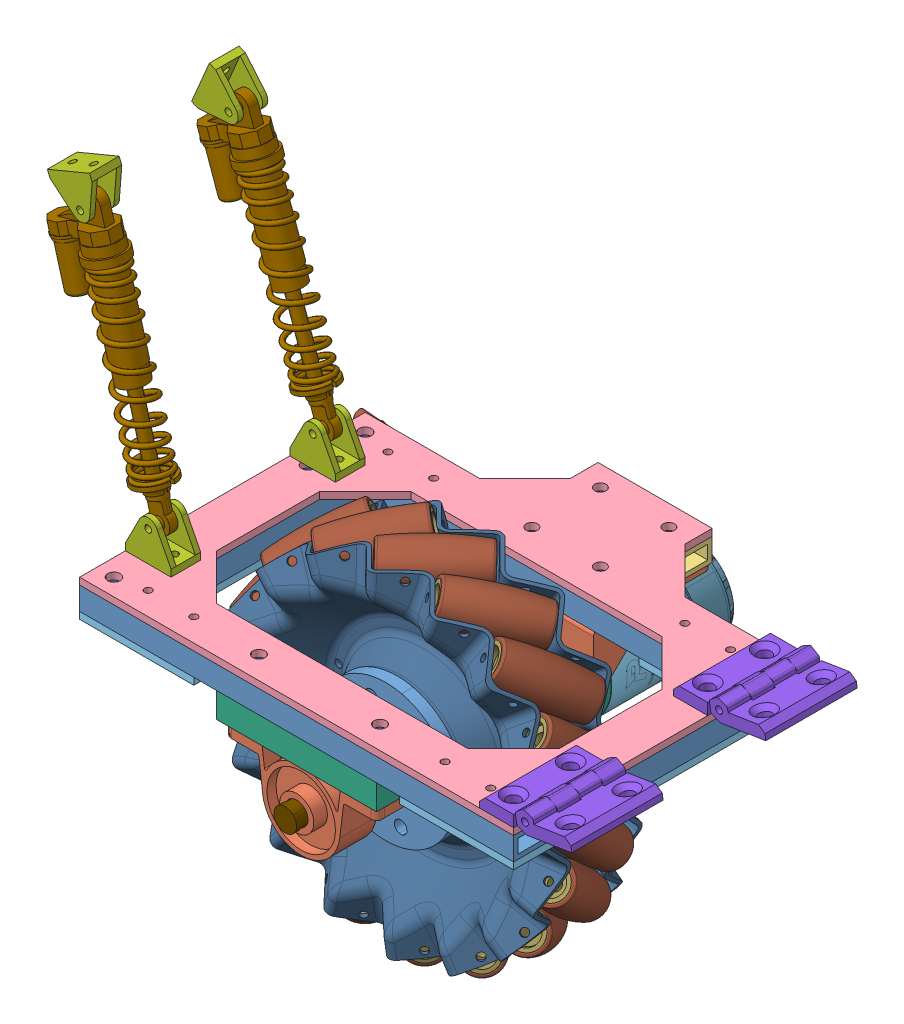
SolidWorks assembly suspension-R, configuration 默认. Lengths in mm.
Overall size (264.55 284.01 183.1).
217 component instances, 35 part files, 56 mates.
Components (placement in the parent):
- Al_Structure-1: Al_Structure [默认] at (-46.393 -16.6731 0) size (190 10 125)
- 3508_10电机座-1: 3508_10电机座 [Default] at (24.7457 -16.6731 39.834) x (-1 0 0) z (0 0 1) size (50 52 52)
- M3508直流无刷减速电机-1: M3508直流无刷减速电机 [默认] at (-63.9604 -40.3546 -130.941) x (-0.381788 -0.92425 0) z (0 0 1) size (81.79 158.79 98.4)
  - M3508直流无刷减速电机.STEP-1: M3508直流无刷减速电机.STEP [Default] at origin size (81.79 158.79 98.4)
    - 2.STEP-1: 2.STEP [Default] at (-1.7887 18.2683 50.441) x (-0.381788 0.92425 0) z (0.92425 0.381788 0) size (59.4 63.3 59.4)
      - 26.STEP-1: 26.STEP [Default] at (0 27 0) x (-0.381788 0 0.92425) z (-0.92425 0 -0.381788) size (22 6 22)
        - 27.STEP-1: 27.STEP [默认] at origin size (22 6 22)
        - 28.STEP-1: 28.STEP [默认] at (0 2.5 0) size (20 0.2 20)
        - 28.STEP-2: 28.STEP [默认] at (0 -2.7 0) size (20 0.2 20)
      - 26.STEP-2: 26.STEP [Default] at (0 34.5 0) x (-0.381788 0 0.92425) z (-0.92425 0 -0.381788) size (22 6 22)
        - 27.STEP-1: 27.STEP [默认] at origin size (22 6 22)
        - 28.STEP-1: 28.STEP [默认] at (0 2.5 0) size (20 0.2 20)
        - 28.STEP-2: 28.STEP [默认] at (0 -2.7 0) size (20 0.2 20)
      - 23.STEP-1: 23.STEP [默认] at origin size (42.01 26 42)
      - 16.STEP-1: 16.STEP [默认] at (0 31 0) x (-0.707107 0 0.707107) z (0 1 0) size (42 42 14)
      - 25.STEP-1: 25.STEP [默认] at (0 38.5 0) x (0 0 1) z (-1 0 0) size (16.7 1 13.43)
      - 17.STEP-1: 17.STEP [默认] at (0 19.3 0) x (-1 0 0) z (0 0 -1) size (26 44 26)
      - 24.STEP-1: 24.STEP [默认] at (0 37.71 0) x (0 1 0) z (0.381788 0 -0.92425) size (0.42 16 16)
      - 18.STEP-1: 18.STEP [默认] at (12.3744 22 12.3744) x (-0.381788 0 0.92425) z (-0.92425 0 -0.381788) size (5.5 12 5.5)
      - 18.STEP-2: 18.STEP [默认] at (12.3744 22 -12.3744) x (0.92425 0 0.381788) z (-0.381788 0 0.92425) size (5.5 12 5.5)
      - 18.STEP-3: 18.STEP [默认] at (-12.3744 22 -12.3744) x (0.381788 0 -0.92425) z (0.92425 0 0.381788) size (5.5 12 5.5)
      - 18.STEP-4: 18.STEP [默认] at (-12.3744 22 12.3744) x (-0.92425 0 -0.381788) z (0.381788 0 -0.92425) size (5.5 12 5.5)
    - 5.STEP-1: 5.STEP [Default] at (56.824 -105.7062 43.091) x (0.954008 0.299781 0) z (-0.299781 0.954008 0) size (12.31 5.48 111.01)
      - 19.STEP-1: 19.STEP [默认] at origin size (12.31 5.48 13.41)
      - 15.STEP-1: 15.STEP [默认] at (-22.7519 0 22.9937) x (-1 0 0) z (0 0 -1) size (2.5 2.5 100)
      - 15.STEP-2: 15.STEP [默认] at (-18.7519 0 22.9937) x (0 1 0) z (0 0 -1) size (2.5 2.5 100)
      - 15.STEP-3: 15.STEP [默认] at (-14.7519 0 22.9937) x (-1 0 0) z (0 0 -1) size (2.5 2.5 100)
      - 20.STEP-1: 20.STEP [默认] at (-1.9783 -5.4851 11.3276) x (1 0 0) z (0 0 -1) size (11.93 4.93 6.5)
    - 1.STEP-1: 1.STEP [默认] at (-1.7887 18.2683 48.441) x (0.923508 -0.383579 0) z (0 0 1) size (42 42 43.4)
    - 4.STEP-1: 4.STEP [默认] at (-1.7887 18.2683 39.841) x (-0.923508 0.383579 0) z (0.383579 0.923508 0) size (13.16 4.25 21.29)
    - 3.STEP-1: 3.STEP [默认] at (4.5067 -1.7659 43.091) x (0.299781 -0.954008 0) z (0.954008 0.299781 0) size (5.77 4 14.5)
- 3510D孔联轴器-1: 3510D孔联轴器 [Default] at (-128.3393 -63.9318 -10.2) x (0.685829 0.727763 0) z (-0.727763 0.685829 0) size (60 27 60)
- 10mm钢制联轴器-1: 10mm钢制联轴器 [默认] at (-49.6804 -47.7533 1.2992) x (0.685829 0.727763 0) z (0 0 1) size (81.96 81.96 49.1)
  - 10mm钢制联轴器.STEP-1: 10mm钢制联轴器.STEP [Default] at origin size (81.96 81.96 49.1)
    - __________.STEP-1: __________.STEP [Default] at (3.7664 -0.9677 32.1012) size (24 24 44.1)
    - 3510______ ____2.STEP-1: 3510______ ____2.STEP [Default] at (9.8274 82.7684 22.1012) x (0.5 -0.866025 0) z (0.866025 0.5 0) size (60 5 60)
- 10mmBearingSet-1: 10mmBearingSet [默认] at (-47.6247 -31.9408 44.5) x (-1 0 0) z (0 0 1) size (67 35 18)
- 电机座垫铝管-1: 电机座垫铝管 [Default] at (24.7457 -16.6731 39.834) x (1 0 0) z (0 1 0) size (50 20 10)
- 玻纤上板-1: 玻纤上板 [Default] at (-46.393 -6.6731 0) x (1 0 0) z (0 1 0) size (190 157 3)
- 玻纤下板-1: 玻纤下板 [Default] at (-46.393 -16.6731 0) x (-1 0 0) z (0 -1 0) size (50 125 3)
- 玻纤下板-2: 玻纤下板 [Default] at (-46.393 -16.6731 0) x (1 0 0) z (0 -1 0) size (50 125 3)
- 3DPrinting垫片-1: 3DPrinting垫片 [Default] at (-46.393 -16.6731 0) x (-1 0 0) z (0 -1 0) size (70 20 11)
- 3mm固定座-1: 3mm固定座 [Default] at (-166.7361 -3.6731 11.7194) size (20 17.54 13)
- 3mm固定座-2: 3mm固定座 [Default] at (-166.7361 -3.6731 83.7194) size (20 17.54 13)
- 铰链-1: 铰链 [默认] at (42.216 2.468 -82.5) x (-1 0 0) z (0 0 1) size (40.48 12.73 40)
  - 铰链-1: 铰链 [默认] at (-11.391 1.5222 20) size (24 9.08 40)
  - 铰链-2: 铰链 [默认] at (-11.391 1.5222 60) x (-0.987641 -0.156733 0) z (0 0 -1) size (24 9.08 40)
- 铰链-2: 铰链 [默认] at (42.216 2.468 2.5) x (-1 0 0) z (0 0 1) size (40.48 12.73 40)
  - 铰链-1: 铰链 [默认] at (-11.391 1.5222 20) size (24 9.08 40)
  - 铰链-2: 铰链 [默认] at (-11.391 1.5222 60) x (-0.987641 -0.156733 0) z (0 0 -1) size (24 9.08 40)
- 孔距110mm负压避震器.-1: 孔距110mm负压避震器. [默认] at (-170.847 94.2339 -2.4) x (-0.96253 -0.271174 0) z (0 0 1) size (30.38 119.45 17)
- 孔距110mm负压避震器.-2: 孔距110mm负压避震器. [默认] at (-176.4374 91.3946 -74.4) x (-0.942156 -0.335174 0) z (0 0 1) size (30.38 119.45 17)
- 3mm固定座-3: 3mm固定座 [Default] at (-133.7096 141.372 83.7194) x (-0.923129 -0.38449 0) z (0 0 1) size (20 17.54 13)
- 3mm固定座-4: 3mm固定座 [Default] at (-166.7199 150.9953 11.7194) x (-0.390129 -0.92076 0) z (0 0 1) size (20 17.54 13)
- 麦轮组装左-1: 麦轮组装左 [默认] at (-29.0896 -59.734 -126.7518) x (0.945939 -0.324344 0) z (0 0 1) size (168 168 53.18)
  - 麦轮钣金-1: 麦轮钣金 [默认] at (-20.9276 7.6858 132.4522) size (142.88 142.88 24.05)
  - 麦轮钣金-2: 麦轮钣金 [默认] at (-20.9276 7.6858 129.2518) x (-0.980785 -0.19509 0) z (0 0 -1) size (142.88 142.88 24.05)
  - 滚花橡胶轮组装-1: 滚花橡胶轮组装 [默认] at (60.4121 -1.9858 154.8754) x (0.932849 -0.320965 -0.163627) z (-0.338043 -0.622763 -0.705615) size (18.5 18.5 53)
    - 滚花橡胶轮外-1: 滚花橡胶轮外 [默认] at (-9.896 1.7835 38.5971) size (18.5 18.5 38)
    - 滚花铝柱-1: 滚花铝柱 [默认] at (-9.896 1.7835 38) x (0.787441 0.61639 0) z (-0.61639 0.787441 0) size (13 38 13)
    - 轴承5X10X4-1: 轴承5X10X4 [默认] at (-9.896 1.7835 55) x (0.442498 0.896769 0) z (-0.896769 0.442498 0) size (10 4 10)
    - 轴承5X10X4-2: 轴承5X10X4 [默认] at (-9.896 1.7835 21) x (0.442498 0.896769 0) z (-0.896769 0.442498 0) size (10 4 10)
    - 铜管3X5-1: 铜管3X5 [默认] at (-9.896 1.7835 38) x (0.823254 0.567673 0) z (-0.567673 0.823254 0) size (5 38 5)
    - 螺丝-1: 螺丝 [默认] at (-9.896 1.7835 59.6) x (-0.462621 0.886556 0) z (0 0 1) size (5.5 5.5 53)
    - 垫片-1: 垫片 [默认] at (-9.896 1.7835 57) x (1 0 0) z (0 -1 0) size (7 0.8 7)
    - 垫片-2: 垫片 [默认] at (-9.896 1.7835 19) x (0.746862 -0.664979 0) z (0.664979 0.746862 0) size (7 0.8 7)
    - 螺母-1: 螺母 [默认] at (-9.896 1.7835 16.2) x (-0.766894 0.641774 0) z (0 0 -1) size (6.35 5.5 4.25)
  - 滚花橡胶轮组装-2: 滚花橡胶轮组装 [默认] at (57.9216 29.8777 154.8754) x (0.984668 0.060453 -0.163627) z (-0.073989 -0.704722 -0.705615) size (18.5 18.5 53)
    - 滚花橡胶轮外-1: 滚花橡胶轮外 [默认] at (-9.896 1.7835 38.5971) size (18.5 18.5 38)
    - 滚花铝柱-1: 滚花铝柱 [默认] at (-9.896 1.7835 38) x (0.787441 0.61639 0) z (-0.61639 0.787441 0) size (13 38 13)
    - 轴承5X10X4-1: 轴承5X10X4 [默认] at (-9.896 1.7835 55) x (0.442498 0.896769 0) z (-0.896769 0.442498 0) size (10 4 10)
    - 轴承5X10X4-2: 轴承5X10X4 [默认] at (-9.896 1.7835 21) x (0.442498 0.896769 0) z (-0.896769 0.442498 0) size (10 4 10)
    - 铜管3X5-1: 铜管3X5 [默认] at (-9.896 1.7835 38) x (0.823254 0.567673 0) z (-0.567673 0.823254 0) size (5 38 5)
    - 螺丝-1: 螺丝 [默认] at (-9.896 1.7835 59.6) x (-0.462621 0.886556 0) z (0 0 1) size (5.5 5.5 53)
    - 垫片-1: 垫片 [默认] at (-9.896 1.7835 57) x (1 0 0) z (0 -1 0) size (7 0.8 7)
    - 垫片-2: 垫片 [默认] at (-9.896 1.7835 19) x (0.746862 -0.664979 0) z (0.664979 0.746862 0) size (7 0.8 7)
    - 螺母-1: 螺母 [默认] at (-9.896 1.7835 16.2) x (-0.766894 0.641774 0) z (0 0 -1) size (6.35 5.5 4.25)
  - 滚花橡胶轮组装-3: 滚花橡胶轮组装 [默认] at (43.4271 58.3628 154.8754) x (0.88658 0.432668 -0.163627) z (0.201328 -0.679392 -0.705615) size (18.5 18.5 53)
    - 滚花橡胶轮外-1: 滚花橡胶轮外 [默认] at (-9.896 1.7835 38.5971) size (18.5 18.5 38)
    - 滚花铝柱-1: 滚花铝柱 [默认] at (-9.896 1.7835 38) x (0.787441 0.61639 0) z (-0.61639 0.787441 0) size (13 38 13)
    - 轴承5X10X4-1: 轴承5X10X4 [默认] at (-9.896 1.7835 55) x (0.442498 0.896769 0) z (-0.896769 0.442498 0) size (10 4 10)
    - 轴承5X10X4-2: 轴承5X10X4 [默认] at (-9.896 1.7835 21) x (0.442498 0.896769 0) z (-0.896769 0.442498 0) size (10 4 10)
    - 铜管3X5-1: 铜管3X5 [默认] at (-9.896 1.7835 38) x (0.823254 0.567673 0) z (-0.567673 0.823254 0) size (5 38 5)
    - 螺丝-1: 螺丝 [默认] at (-9.896 1.7835 59.6) x (-0.462621 0.886556 0) z (0 0 1) size (5.5 5.5 53)
    - 垫片-1: 垫片 [默认] at (-9.896 1.7835 57) x (1 0 0) z (0 -1 0) size (7 0.8 7)
    - 垫片-2: 垫片 [默认] at (-9.896 1.7835 19) x (0.746862 -0.664979 0) z (0.664979 0.746862 0) size (7 0.8 7)
    - 螺母-1: 螺母 [默认] at (-9.896 1.7835 16.2) x (-0.766894 0.641774 0) z (0 0 -1) size (6.35 5.5 4.25)
  - 滚花橡胶轮组装-4: 滚花橡胶轮组装 [默认] at (19.1352 79.1327 154.8754) x (0.653519 0.739013 -0.163627) z (0.445995 -0.550632 -0.705615) size (18.5 18.5 53)
    - 滚花橡胶轮外-1: 滚花橡胶轮外 [默认] at (-9.896 1.7835 38.5971) size (18.5 18.5 38)
    - 滚花铝柱-1: 滚花铝柱 [默认] at (-9.896 1.7835 38) x (0.787441 0.61639 0) z (-0.61639 0.787441 0) size (13 38 13)
    - 轴承5X10X4-1: 轴承5X10X4 [默认] at (-9.896 1.7835 55) x (0.442498 0.896769 0) z (-0.896769 0.442498 0) size (10 4 10)
    - 轴承5X10X4-2: 轴承5X10X4 [默认] at (-9.896 1.7835 21) x (0.442498 0.896769 0) z (-0.896769 0.442498 0) size (10 4 10)
    - 铜管3X5-1: 铜管3X5 [默认] at (-9.896 1.7835 38) x (0.823254 0.567673 0) z (-0.567673 0.823254 0) size (5 38 5)
    - 螺丝-1: 螺丝 [默认] at (-9.896 1.7835 59.6) x (-0.462621 0.886556 0) z (0 0 1) size (5.5 5.5 53)
    - 垫片-1: 垫片 [默认] at (-9.896 1.7835 57) x (1 0 0) z (0 -1 0) size (7 0.8 7)
    - 垫片-2: 垫片 [默认] at (-9.896 1.7835 19) x (0.746862 -0.664979 0) z (0.664979 0.746862 0) size (7 0.8 7)
    - 螺母-1: 螺母 [默认] at (-9.896 1.7835 16.2) x (-0.766894 0.641774 0) z (0 0 -1) size (6.35 5.5 4.25)
  - 滚花橡胶轮组装-5: 滚花橡胶轮组装 [默认] at (-11.256 89.0255 154.8754) x (0.320965 0.932849 -0.163627) z (0.622763 -0.338043 -0.705615) size (18.5 18.5 53)
    - 滚花橡胶轮外-1: 滚花橡胶轮外 [默认] at (-9.896 1.7835 38.5971) size (18.5 18.5 38)
    - 滚花铝柱-1: 滚花铝柱 [默认] at (-9.896 1.7835 38) x (0.787441 0.61639 0) z (-0.61639 0.787441 0) size (13 38 13)
    - 轴承5X10X4-1: 轴承5X10X4 [默认] at (-9.896 1.7835 55) x (0.442498 0.896769 0) z (-0.896769 0.442498 0) size (10 4 10)
    - 轴承5X10X4-2: 轴承5X10X4 [默认] at (-9.896 1.7835 21) x (0.442498 0.896769 0) z (-0.896769 0.442498 0) size (10 4 10)
    - 铜管3X5-1: 铜管3X5 [默认] at (-9.896 1.7835 38) x (0.823254 0.567673 0) z (-0.567673 0.823254 0) size (5 38 5)
    - 螺丝-1: 螺丝 [默认] at (-9.896 1.7835 59.6) x (-0.462621 0.886556 0) z (0 0 1) size (5.5 5.5 53)
    - 垫片-1: 垫片 [默认] at (-9.896 1.7835 57) x (1 0 0) z (0 -1 0) size (7 0.8 7)
    - 垫片-2: 垫片 [默认] at (-9.896 1.7835 19) x (0.746862 -0.664979 0) z (0.664979 0.746862 0) size (7 0.8 7)
    - 螺母-1: 螺母 [默认] at (-9.896 1.7835 16.2) x (-0.766894 0.641774 0) z (0 0 -1) size (6.35 5.5 4.25)
  - 滚花橡胶轮组装-6: 滚花橡胶轮组装 [默认] at (-43.1195 86.535 154.8754) x (-0.060453 0.984668 -0.163627) z (0.704722 -0.073989 -0.705615) size (18.5 18.5 53)
    - 滚花橡胶轮外-1: 滚花橡胶轮外 [默认] at (-9.896 1.7835 38.5971) size (18.5 18.5 38)
    - 滚花铝柱-1: 滚花铝柱 [默认] at (-9.896 1.7835 38) x (0.787441 0.61639 0) z (-0.61639 0.787441 0) size (13 38 13)
    - 轴承5X10X4-1: 轴承5X10X4 [默认] at (-9.896 1.7835 55) x (0.442498 0.896769 0) z (-0.896769 0.442498 0) size (10 4 10)
    - 轴承5X10X4-2: 轴承5X10X4 [默认] at (-9.896 1.7835 21) x (0.442498 0.896769 0) z (-0.896769 0.442498 0) size (10 4 10)
    - 铜管3X5-1: 铜管3X5 [默认] at (-9.896 1.7835 38) x (0.823254 0.567673 0) z (-0.567673 0.823254 0) size (5 38 5)
    - 螺丝-1: 螺丝 [默认] at (-9.896 1.7835 59.6) x (-0.462621 0.886556 0) z (0 0 1) size (5.5 5.5 53)
    - 垫片-1: 垫片 [默认] at (-9.896 1.7835 57) x (1 0 0) z (0 -1 0) size (7 0.8 7)
    - 垫片-2: 垫片 [默认] at (-9.896 1.7835 19) x (0.746862 -0.664979 0) z (0.664979 0.746862 0) size (7 0.8 7)
    - 螺母-1: 螺母 [默认] at (-9.896 1.7835 16.2) x (-0.766894 0.641774 0) z (0 0 -1) size (6.35 5.5 4.25)
  - 滚花橡胶轮组装-7: 滚花橡胶轮组装 [默认] at (-71.6045 72.0405 154.8754) x (-0.432668 0.88658 -0.163627) z (0.679392 0.201328 -0.705615) size (18.5 18.5 53)
    - 滚花橡胶轮外-1: 滚花橡胶轮外 [默认] at (-9.896 1.7835 38.5971) size (18.5 18.5 38)
    - 滚花铝柱-1: 滚花铝柱 [默认] at (-9.896 1.7835 38) x (0.787441 0.61639 0) z (-0.61639 0.787441 0) size (13 38 13)
    - 轴承5X10X4-1: 轴承5X10X4 [默认] at (-9.896 1.7835 55) x (0.442498 0.896769 0) z (-0.896769 0.442498 0) size (10 4 10)
    - 轴承5X10X4-2: 轴承5X10X4 [默认] at (-9.896 1.7835 21) x (0.442498 0.896769 0) z (-0.896769 0.442498 0) size (10 4 10)
    - 铜管3X5-1: 铜管3X5 [默认] at (-9.896 1.7835 38) x (0.823254 0.567673 0) z (-0.567673 0.823254 0) size (5 38 5)
    - 螺丝-1: 螺丝 [默认] at (-9.896 1.7835 59.6) x (-0.462621 0.886556 0) z (0 0 1) size (5.5 5.5 53)
    - 垫片-1: 垫片 [默认] at (-9.896 1.7835 57) x (1 0 0) z (0 -1 0) size (7 0.8 7)
    - 垫片-2: 垫片 [默认] at (-9.896 1.7835 19) x (0.746862 -0.664979 0) z (0.664979 0.746862 0) size (7 0.8 7)
    - 螺母-1: 螺母 [默认] at (-9.896 1.7835 16.2) x (-0.766894 0.641774 0) z (0 0 -1) size (6.35 5.5 4.25)
  - 滚花橡胶轮组装-8: 滚花橡胶轮组装 [默认] at (-92.3745 47.7486 154.8754) x (-0.739013 0.653519 -0.163627) z (0.550632 0.445995 -0.705615) size (18.5 18.5 53)
    - 滚花橡胶轮外-1: 滚花橡胶轮外 [默认] at (-9.896 1.7835 38.5971) size (18.5 18.5 38)
    - 滚花铝柱-1: 滚花铝柱 [默认] at (-9.896 1.7835 38) x (0.787441 0.61639 0) z (-0.61639 0.787441 0) size (13 38 13)
    - 轴承5X10X4-1: 轴承5X10X4 [默认] at (-9.896 1.7835 55) x (0.442498 0.896769 0) z (-0.896769 0.442498 0) size (10 4 10)
    - 轴承5X10X4-2: 轴承5X10X4 [默认] at (-9.896 1.7835 21) x (0.442498 0.896769 0) z (-0.896769 0.442498 0) size (10 4 10)
    - 铜管3X5-1: 铜管3X5 [默认] at (-9.896 1.7835 38) x (0.823254 0.567673 0) z (-0.567673 0.823254 0) size (5 38 5)
    - 螺丝-1: 螺丝 [默认] at (-9.896 1.7835 59.6) x (-0.462621 0.886556 0) z (0 0 1) size (5.5 5.5 53)
    - 垫片-1: 垫片 [默认] at (-9.896 1.7835 57) x (1 0 0) z (0 -1 0) size (7 0.8 7)
    - 垫片-2: 垫片 [默认] at (-9.896 1.7835 19) x (0.746862 -0.664979 0) z (0.664979 0.746862 0) size (7 0.8 7)
    - 螺母-1: 螺母 [默认] at (-9.896 1.7835 16.2) x (-0.766894 0.641774 0) z (0 0 -1) size (6.35 5.5 4.25)
  - 滚花橡胶轮组装-9: 滚花橡胶轮组装 [默认] at (-102.2673 17.3574 154.8754) x (-0.932849 0.320965 -0.163627) z (0.338043 0.622763 -0.705615) size (18.5 18.5 53)
    - 滚花橡胶轮外-1: 滚花橡胶轮外 [默认] at (-9.896 1.7835 38.5971) size (18.5 18.5 38)
    - 滚花铝柱-1: 滚花铝柱 [默认] at (-9.896 1.7835 38) x (0.787441 0.61639 0) z (-0.61639 0.787441 0) size (13 38 13)
    - 轴承5X10X4-1: 轴承5X10X4 [默认] at (-9.896 1.7835 55) x (0.442498 0.896769 0) z (-0.896769 0.442498 0) size (10 4 10)
    - 轴承5X10X4-2: 轴承5X10X4 [默认] at (-9.896 1.7835 21) x (0.442498 0.896769 0) z (-0.896769 0.442498 0) size (10 4 10)
    - 铜管3X5-1: 铜管3X5 [默认] at (-9.896 1.7835 38) x (0.823254 0.567673 0) z (-0.567673 0.823254 0) size (5 38 5)
    - 螺丝-1: 螺丝 [默认] at (-9.896 1.7835 59.6) x (-0.462621 0.886556 0) z (0 0 1) size (5.5 5.5 53)
    - 垫片-1: 垫片 [默认] at (-9.896 1.7835 57) x (1 0 0) z (0 -1 0) size (7 0.8 7)
    - 垫片-2: 垫片 [默认] at (-9.896 1.7835 19) x (0.746862 -0.664979 0) z (0.664979 0.746862 0) size (7 0.8 7)
    - 螺母-1: 螺母 [默认] at (-9.896 1.7835 16.2) x (-0.766894 0.641774 0) z (0 0 -1) size (6.35 5.5 4.25)
  - 滚花橡胶轮组装-10: 滚花橡胶轮组装 [默认] at (-99.7768 -14.5061 154.8754) x (-0.984668 -0.060453 -0.163627) z (0.073989 0.704722 -0.705615) size (18.5 18.5 53)
    - 滚花橡胶轮外-1: 滚花橡胶轮外 [默认] at (-9.896 1.7835 38.5971) size (18.5 18.5 38)
    - 滚花铝柱-1: 滚花铝柱 [默认] at (-9.896 1.7835 38) x (0.787441 0.61639 0) z (-0.61639 0.787441 0) size (13 38 13)
    - 轴承5X10X4-1: 轴承5X10X4 [默认] at (-9.896 1.7835 55) x (0.442498 0.896769 0) z (-0.896769 0.442498 0) size (10 4 10)
    - 轴承5X10X4-2: 轴承5X10X4 [默认] at (-9.896 1.7835 21) x (0.442498 0.896769 0) z (-0.896769 0.442498 0) size (10 4 10)
    - 铜管3X5-1: 铜管3X5 [默认] at (-9.896 1.7835 38) x (0.823254 0.567673 0) z (-0.567673 0.823254 0) size (5 38 5)
    - 螺丝-1: 螺丝 [默认] at (-9.896 1.7835 59.6) x (-0.462621 0.886556 0) z (0 0 1) size (5.5 5.5 53)
    - 垫片-1: 垫片 [默认] at (-9.896 1.7835 57) x (1 0 0) z (0 -1 0) size (7 0.8 7)
    - 垫片-2: 垫片 [默认] at (-9.896 1.7835 19) x (0.746862 -0.664979 0) z (0.664979 0.746862 0) size (7 0.8 7)
    - 螺母-1: 螺母 [默认] at (-9.896 1.7835 16.2) x (-0.766894 0.641774 0) z (0 0 -1) size (6.35 5.5 4.25)
  - 滚花橡胶轮组装-11: 滚花橡胶轮组装 [默认] at (-85.2823 -42.9912 154.8754) x (-0.88658 -0.432668 -0.163627) z (-0.201328 0.679392 -0.705615) size (18.5 18.5 53)
    - 滚花橡胶轮外-1: 滚花橡胶轮外 [默认] at (-9.896 1.7835 38.5971) size (18.5 18.5 38)
    - 滚花铝柱-1: 滚花铝柱 [默认] at (-9.896 1.7835 38) x (0.787441 0.61639 0) z (-0.61639 0.787441 0) size (13 38 13)
    - 轴承5X10X4-1: 轴承5X10X4 [默认] at (-9.896 1.7835 55) x (0.442498 0.896769 0) z (-0.896769 0.442498 0) size (10 4 10)
    - 轴承5X10X4-2: 轴承5X10X4 [默认] at (-9.896 1.7835 21) x (0.442498 0.896769 0) z (-0.896769 0.442498 0) size (10 4 10)
    - 铜管3X5-1: 铜管3X5 [默认] at (-9.896 1.7835 38) x (0.823254 0.567673 0) z (-0.567673 0.823254 0) size (5 38 5)
    - 螺丝-1: 螺丝 [默认] at (-9.896 1.7835 59.6) x (-0.462621 0.886556 0) z (0 0 1) size (5.5 5.5 53)
    - 垫片-1: 垫片 [默认] at (-9.896 1.7835 57) x (1 0 0) z (0 -1 0) size (7 0.8 7)
    - 垫片-2: 垫片 [默认] at (-9.896 1.7835 19) x (0.746862 -0.664979 0) z (0.664979 0.746862 0) size (7 0.8 7)
    - 螺母-1: 螺母 [默认] at (-9.896 1.7835 16.2) x (-0.766894 0.641774 0) z (0 0 -1) size (6.35 5.5 4.25)
  - 滚花橡胶轮组装-12: 滚花橡胶轮组装 [默认] at (-60.9904 -63.7611 154.8754) x (-0.653519 -0.739013 -0.163627) z (-0.445995 0.550632 -0.705615) size (18.5 18.5 53)
    - 滚花橡胶轮外-1: 滚花橡胶轮外 [默认] at (-9.896 1.7835 38.5971) size (18.5 18.5 38)
    - 滚花铝柱-1: 滚花铝柱 [默认] at (-9.896 1.7835 38) x (0.787441 0.61639 0) z (-0.61639 0.787441 0) size (13 38 13)
    - 轴承5X10X4-1: 轴承5X10X4 [默认] at (-9.896 1.7835 55) x (0.442498 0.896769 0) z (-0.896769 0.442498 0) size (10 4 10)
    - 轴承5X10X4-2: 轴承5X10X4 [默认] at (-9.896 1.7835 21) x (0.442498 0.896769 0) z (-0.896769 0.442498 0) size (10 4 10)
    - 铜管3X5-1: 铜管3X5 [默认] at (-9.896 1.7835 38) x (0.823254 0.567673 0) z (-0.567673 0.823254 0) size (5 38 5)
    - 螺丝-1: 螺丝 [默认] at (-9.896 1.7835 59.6) x (-0.462621 0.886556 0) z (0 0 1) size (5.5 5.5 53)
    - 垫片-1: 垫片 [默认] at (-9.896 1.7835 57) x (1 0 0) z (0 -1 0) size (7 0.8 7)
    - 垫片-2: 垫片 [默认] at (-9.896 1.7835 19) x (0.746862 -0.664979 0) z (0.664979 0.746862 0) size (7 0.8 7)
    - 螺母-1: 螺母 [默认] at (-9.896 1.7835 16.2) x (-0.766894 0.641774 0) z (0 0 -1) size (6.35 5.5 4.25)
  - 滚花橡胶轮组装-13: 滚花橡胶轮组装 [默认] at (-30.5992 -73.6539 154.8754) x (-0.320965 -0.932849 -0.163627) z (-0.622763 0.338043 -0.705615) size (18.5 18.5 53)
    - 滚花橡胶轮外-1: 滚花橡胶轮外 [默认] at (-9.896 1.7835 38.5971) size (18.5 18.5 38)
    - 滚花铝柱-1: 滚花铝柱 [默认] at (-9.896 1.7835 38) x (0.787441 0.61639 0) z (-0.61639 0.787441 0) size (13 38 13)
    - 轴承5X10X4-1: 轴承5X10X4 [默认] at (-9.896 1.7835 55) x (0.442498 0.896769 0) z (-0.896769 0.442498 0) size (10 4 10)
    - 轴承5X10X4-2: 轴承5X10X4 [默认] at (-9.896 1.7835 21) x (0.442498 0.896769 0) z (-0.896769 0.442498 0) size (10 4 10)
    - 铜管3X5-1: 铜管3X5 [默认] at (-9.896 1.7835 38) x (0.823254 0.567673 0) z (-0.567673 0.823254 0) size (5 38 5)
    - 螺丝-1: 螺丝 [默认] at (-9.896 1.7835 59.6) x (-0.462621 0.886556 0) z (0 0 1) size (5.5 5.5 53)
    - 垫片-1: 垫片 [默认] at (-9.896 1.7835 57) x (1 0 0) z (0 -1 0) size (7 0.8 7)
    - 垫片-2: 垫片 [默认] at (-9.896 1.7835 19) x (0.746862 -0.664979 0) z (0.664979 0.746862 0) size (7 0.8 7)
    - 螺母-1: 螺母 [默认] at (-9.896 1.7835 16.2) x (-0.766894 0.641774 0) z (0 0 -1) size (6.35 5.5 4.25)
  - 滚花橡胶轮组装-14: 滚花橡胶轮组装 [默认] at (1.2643 -71.1634 154.8754) x (0.060453 -0.984668 -0.163627) z (-0.704722 0.073989 -0.705615) size (18.5 18.5 53)
    - 滚花橡胶轮外-1: 滚花橡胶轮外 [默认] at (-9.896 1.7835 38.5971) size (18.5 18.5 38)
    - 滚花铝柱-1: 滚花铝柱 [默认] at (-9.896 1.7835 38) x (0.787441 0.61639 0) z (-0.61639 0.787441 0) size (13 38 13)
    - 轴承5X10X4-1: 轴承5X10X4 [默认] at (-9.896 1.7835 55) x (0.442498 0.896769 0) z (-0.896769 0.442498 0) size (10 4 10)
    - 轴承5X10X4-2: 轴承5X10X4 [默认] at (-9.896 1.7835 21) x (0.442498 0.896769 0) z (-0.896769 0.442498 0) size (10 4 10)
    - 铜管3X5-1: 铜管3X5 [默认] at (-9.896 1.7835 38) x (0.823254 0.567673 0) z (-0.567673 0.823254 0) size (5 38 5)
    - 螺丝-1: 螺丝 [默认] at (-9.896 1.7835 59.6) x (-0.462621 0.886556 0) z (0 0 1) size (5.5 5.5 53)
    - 垫片-1: 垫片 [默认] at (-9.896 1.7835 57) x (1 0 0) z (0 -1 0) size (7 0.8 7)
    - 垫片-2: 垫片 [默认] at (-9.896 1.7835 19) x (0.746862 -0.664979 0) z (0.664979 0.746862 0) size (7 0.8 7)
    - 螺母-1: 螺母 [默认] at (-9.896 1.7835 16.2) x (-0.766894 0.641774 0) z (0 0 -1) size (6.35 5.5 4.25)
  - 滚花橡胶轮组装-15: 滚花橡胶轮组装 [默认] at (29.7494 -56.6689 154.8754) x (0.432668 -0.88658 -0.163627) z (-0.679392 -0.201328 -0.705615) size (18.5 18.5 53)
    - 滚花橡胶轮外-1: 滚花橡胶轮外 [默认] at (-9.896 1.7835 38.5971) size (18.5 18.5 38)
    - 滚花铝柱-1: 滚花铝柱 [默认] at (-9.896 1.7835 38) x (0.787441 0.61639 0) z (-0.61639 0.787441 0) size (13 38 13)
    - 轴承5X10X4-1: 轴承5X10X4 [默认] at (-9.896 1.7835 55) x (0.442498 0.896769 0) z (-0.896769 0.442498 0) size (10 4 10)
    - 轴承5X10X4-2: 轴承5X10X4 [默认] at (-9.896 1.7835 21) x (0.442498 0.896769 0) z (-0.896769 0.442498 0) size (10 4 10)
    - 铜管3X5-1: 铜管3X5 [默认] at (-9.896 1.7835 38) x (0.823254 0.567673 0) z (-0.567673 0.823254 0) size (5 38 5)
    - 螺丝-1: 螺丝 [默认] at (-9.896 1.7835 59.6) x (-0.462621 0.886556 0) z (0 0 1) size (5.5 5.5 53)
    - 垫片-1: 垫片 [默认] at (-9.896 1.7835 57) x (1 0 0) z (0 -1 0) size (7 0.8 7)
    - 垫片-2: 垫片 [默认] at (-9.896 1.7835 19) x (0.746862 -0.664979 0) z (0.664979 0.746862 0) size (7 0.8 7)
    - 螺母-1: 螺母 [默认] at (-9.896 1.7835 16.2) x (-0.766894 0.641774 0) z (0 0 -1) size (6.35 5.5 4.25)
  - 滚花橡胶轮组装-16: 滚花橡胶轮组装 [默认] at (50.5193 -32.377 154.8754) x (0.739013 -0.653519 -0.163627) z (-0.550632 -0.445995 -0.705615) size (18.5 18.5 53)
    - 滚花橡胶轮外-1: 滚花橡胶轮外 [默认] at (-9.896 1.7835 38.5971) size (18.5 18.5 38)
    - 滚花铝柱-1: 滚花铝柱 [默认] at (-9.896 1.7835 38) x (0.787441 0.61639 0) z (-0.61639 0.787441 0) size (13 38 13)
    - 轴承5X10X4-1: 轴承5X10X4 [默认] at (-9.896 1.7835 55) x (0.442498 0.896769 0) z (-0.896769 0.442498 0) size (10 4 10)
    - 轴承5X10X4-2: 轴承5X10X4 [默认] at (-9.896 1.7835 21) x (0.442498 0.896769 0) z (-0.896769 0.442498 0) size (10 4 10)
    - 铜管3X5-1: 铜管3X5 [默认] at (-9.896 1.7835 38) x (0.823254 0.567673 0) z (-0.567673 0.823254 0) size (5 38 5)
    - 螺丝-1: 螺丝 [默认] at (-9.896 1.7835 59.6) x (-0.462621 0.886556 0) z (0 0 1) size (5.5 5.5 53)
    - 垫片-1: 垫片 [默认] at (-9.896 1.7835 57) x (1 0 0) z (0 -1 0) size (7 0.8 7)
    - 垫片-2: 垫片 [默认] at (-9.896 1.7835 19) x (0.746862 -0.664979 0) z (0.664979 0.746862 0) size (7 0.8 7)
    - 螺母-1: 螺母 [默认] at (-9.896 1.7835 16.2) x (-0.766894 0.641774 0) z (0 0 -1) size (6.35 5.5 4.25)
Mates (geometry in assembly coordinates):
- Coincident1: coincident: plane of assembly; plane of assembly; plane of 3508_10电机座-1 through (-68.393 -65.6731 -44.5) normal (0 0 -1); plane of M3508直流无刷减速电机-1/M3508直流无刷减速电机.STEP-1/2.STEP-1/16.STEP-1 through (-55.5854 -36.4836 -44.5) normal (0 0 1)
- Concentric1: concentric: cylinder of assembly; cylinder of assembly; cylinder of 3508_10电机座-1 through (-46.393 -45.6759 -42.5) axis (0 0 -1) radius 13; cylinder of M3508直流无刷减速电机-1/M3508直流无刷减速电机.STEP-1/2.STEP-1/16.STEP-1 through (-46.393 -45.6759 -25.3808) axis (0 0 1) radius 13
- Concentric2: concentric: cylinder of assembly; cylinder of assembly; cylinder of 3508_10电机座-1 through (-46.393 -63.1759 -42.5) axis (0 0 -1) radius 2; cylinder of M3508直流无刷减速电机-1/M3508直流无刷减速电机.STEP-1/2.STEP-1/16.STEP-1 through (-46.393 -63.1759 -44.5) axis (0 0 1) radius 1.65
- Coincident2: coincident: plane of assembly; plane of assembly; plane of Al_Structure-1 through (-46.393 -16.6731 0) normal (0 -1 0); plane of 3508_10电机座-1 through (-68.393 -16.6731 -91.5) normal (0 1 0)
- Coincident3: coincident: plane of assembly; plane of assembly; plane of Al_Structure-1 through (-121.393 -6.6731 -42.5) normal (0 0 1); plane of 3508_10电机座-1 through (-68.393 -65.6731 -42.5) normal (0 0 1)
- Width1: width: plane of assembly; plane of assembly; plane of assembly; plane of assembly; plane of 3508_10电机座-1 through (-71.393 -18.6731 -91.5) normal (-1 0 0); plane of 3508_10电机座-1 through (-21.393 -18.6731 -44.5) normal (1 0 0); plane of Al_Structure-1 through (48.607 -6.6731 62.5) normal (1 0 0); plane of Al_Structure-1 through (-141.393 -6.6731 62.5) normal (-1 0 0)
- Concentric3: concentric: cylinder of assembly; cylinder of assembly; cylinder of M3508直流无刷减速电机-1/M3508直流无刷减速电机.STEP-1/2.STEP-1/17.STEP-1 through (-46.393 -45.6759 -17.2) axis (0 0 1) radius 5; cylinder of 3510D孔联轴器-1 through (-46.393 -45.6759 -17.2) axis (0 0 -1) radius 5.05
- Coincident4: coincident: plane of assembly; plane of assembly; plane of M3508直流无刷减速电机-1/M3508直流无刷减速电机.STEP-1/2.STEP-1/17.STEP-1 through (-46.393 -45.6759 -37.2) normal (0 0 1); plane of 3510D孔联轴器-1 through (-46.393 -45.6759 -37.2) normal (0 0 -1)
- Concentric8: concentric: cylinder of assembly; cylinder of assembly; cylinder of 10mm钢制联轴器-1/10mm钢制联轴器.STEP-1/__________.STEP-1 through (-46.393 -45.6759 67.5004) axis (0 0 -1) radius 5; cylinder of 10mmBearingSet-1 through (-46.393 -45.6759 60.5) axis (0 0 -1) radius 5
- Parallel1: parallel: plane of assembly; plane of assembly; plane of Al_Structure-1 through (-46.393 -16.6731 0) normal (0 -1 0); plane of 10mmBearingSet-1 through (-12.893 -27.6759 60.5) normal (0 1 0)
- Width2: width: plane of assembly; plane of assembly; plane of assembly; plane of assembly; plane of 10mmBearingSet-1 through (-46.393 -45.6759 60.5) normal (0 0 1); plane of 10mmBearingSet-1 through (-46.393 -45.6759 44.5) normal (0 0 -1); plane of Al_Structure-1 through (-121.393 -6.6731 42.5) normal (0 0 -1); plane of Al_Structure-1 through (-141.393 -6.6731 62.5) normal (0 0 1)
- Inplace1: in place: plane of 3508_10电机座-1 through (-68.393 -16.6731 -91.5) normal (0 1 0); plane of ? through (0 -16.6731 0) normal (0 1 0); moOrthogonalPlaneRef_w of 3508_10电机座-1 through (-68.393 -16.6731 -91.5) normal (0 1 0); plane of ? through (0 -16.6731 0) normal (0 0 -1); plane of 3508_10电机座-1 through (-68.393 -16.6731 -91.5) normal (0 1 0); plane of ? through (0 -16.6731 0) normal (1 0 0); plane of 3508_10电机座-1 through (-68.393 -16.6731 -91.5) normal (0 1 0); unknown of 电机座垫铝管-1
- Coincident9: coincident: plane of assembly; plane of assembly; plane of 3508_10电机座-1; plane of 电机座垫铝管-1
- Coincident10: coincident: plane of assembly; plane of assembly; moOrthogonalPlaneRef_w of 3508_10电机座-1 through (24.7457 -16.6731 39.834) normal (0 0 -1); plane of 电机座垫铝管-1 through (24.7457 -16.6731 39.834) normal (0 0 -1)
- Coincident11: coincident: plane of assembly; plane of assembly; moOrthogonalPlaneRef_w of 3508_10电机座-1 through (24.7457 -16.6731 39.834) normal (-1 0 0); plane of 电机座垫铝管-1 through (24.7457 -16.6731 39.834) normal (1 0 0)
- Inplace2: in place: plane of Al_Structure-1 through (-46.393 -6.6731 0) normal (0 1 0); plane of ? through (0 -6.6731 0) normal (0 1 0); plane of Al_Structure-1 through (-46.393 -6.6731 0) normal (0 1 0); plane of ? through (0 -6.6731 0) normal (0 0 -1); plane of Al_Structure-1 through (-46.393 -6.6731 0) normal (0 1 0); plane of ? through (0 -6.6731 0) normal (1 0 0); plane of Al_Structure-1 through (-46.393 -6.6731 0) normal (0 1 0); unknown of 玻纤上板-1
- Coincident12: coincident: plane of assembly through (-46.393 -6.6731 0) normal (0 1 0); plane of assembly through (-46.393 -6.6731 0) normal (0 1 0); plane of Al_Structure-1; plane of 玻纤上板-1
- Coincident13: coincident: plane of assembly; plane of assembly; moOrthogonalPlaneRef_w of Al_Structure-1 through (-46.393 -6.6731 0) normal (0 0 -1); plane of 玻纤上板-1 through (-46.393 -6.6731 0) normal (0 0 -1)
- Coincident14: coincident: plane of assembly; plane of assembly; moOrthogonalPlaneRef_w of Al_Structure-1 through (-46.393 -6.6731 0) normal (-1 0 0); plane of 玻纤上板-1 through (-46.393 -6.6731 0) normal (1 0 0)
- Inplace3: in place: plane of Al_Structure-1 through (-46.393 -16.6731 0) normal (0 -1 0); plane of ? through (0 -16.6731 0) normal (0 -1 0); plane of Al_Structure-1 through (-46.393 -16.6731 0) normal (0 -1 0); plane of ? through (0 -16.6731 0) normal (0 0 -1); plane of Al_Structure-1 through (-46.393 -16.6731 0) normal (0 -1 0); plane of ? through (0 -16.6731 0) normal (-1 0 0); plane of Al_Structure-1 through (-46.393 -16.6731 0) normal (0 -1 0); unknown of ?
- Coincident15: coincident: plane of assembly; plane of assembly; plane of Al_Structure-1; plane of 玻纤下板-1
- Coincident16: coincident: plane of Al_Structure-1 through (-46.393 -16.6731 0) normal (0 0 -1); plane of ? through (-46.393 -16.6731 0) normal (0 0 -1)
- Coincident17: coincident: plane of Al_Structure-1 through (-46.393 -16.6731 0) normal (1 0 0); plane of ? through (-46.393 -16.6731 0) normal (-1 0 0)
- Coincident18: coincident: plane of assembly; plane of assembly; plane of Al_Structure-1 through (-46.393 -16.6731 0) normal (0 -1 0); plane of 玻纤下板-2 through (-46.393 -16.6731 0) normal (0 1 0)
- Coincident19: coincident: plane of assembly; plane of assembly; plane of Al_Structure-1 through (-141.393 -6.6731 -62.5) normal (0 0 -1); plane of 玻纤下板-2 through (-101.393 -19.6731 -62.5) normal (0 0 -1)
- Coincident20: coincident: plane of assembly; plane of assembly; plane of Al_Structure-1 through (-141.393 -6.6731 62.5) normal (-1 0 0); plane of 玻纤下板-2 through (-141.393 -19.6731 62.5) normal (-1 0 0)
- Inplace4: in place: plane of Al_Structure-1 through (-46.393 -16.6731 0) normal (0 -1 0); plane of ? through (0 -16.6731 0) normal (0 -1 0); plane of Al_Structure-1 through (-46.393 -16.6731 0) normal (0 -1 0); plane of ? through (0 -16.6731 0) normal (0 0 -1); plane of Al_Structure-1 through (-46.393 -16.6731 0) normal (0 -1 0); plane of ? through (0 -16.6731 0) normal (-1 0 0); plane of Al_Structure-1 through (-46.393 -16.6731 0) normal (0 -1 0); unknown of ?
- Coincident21: coincident: plane of assembly; plane of assembly; plane of Al_Structure-1; plane of 3DPrinting垫片-1
- Coincident22: coincident: plane of Al_Structure-1 through (-46.393 -16.6731 0) normal (0 0 -1); plane of ? through (-46.393 -16.6731 0) normal (0 0 -1)
- Coincident23: coincident: plane of Al_Structure-1 through (-46.393 -16.6731 0) normal (1 0 0); plane of ? through (-46.393 -16.6731 0) normal (-1 0 0)
- Coincident24: coincident: plane of assembly; plane of assembly; plane of 玻纤上板-1 through (-46.393 -3.6731 0) normal (0 1 0); plane of 3mm固定座-1 through (-166.7361 -3.6731 11.7194) normal (0 -1 0)
- Distance1: distance = 20 mm: plane of assembly; plane of assembly; plane of 3mm固定座-1 through (-131.393 9.6269 -42.5) normal (0 0 -1); plane of Al_Structure-1 through (-141.393 -6.6731 -62.5) normal (0 0 -1)
- Coincident27: coincident: plane of assembly; plane of assembly; plane of 玻纤上板-1 through (-46.393 -3.6731 0) normal (0 1 0); plane of 3mm固定座-2 through (-166.7361 -3.6731 83.7194) normal (0 -1 0)
- Distance2: distance = 20 mm: plane of 3mm固定座-2 through (-131.393 9.6269 42.5) normal (0 0 1); plane of Al_Structure-1 through (-141.393 -6.6731 62.5) normal (0 0 1)
- Coincident28: coincident: plane of 玻纤上板-1 through (-46.393 -3.6731 0) normal (0 1 0); plane of 铰链-1/铰链-1 through (53.607 -3.6731 -22.5) normal (0 -1 0)
- Coincident31: coincident: plane of 玻纤上板-1 through (-46.393 -3.6731 0) normal (0 1 0); plane of 铰链-2/铰链-1 through (53.607 -3.6731 62.5) normal (0 -1 0)
- Concentric9: concentric: cylinder of 3mm固定座-2 through (-131.393 9.6269 42.5) axis (0 0 -1) radius 1.5; cylinder of 孔距110mm负压避震器.-1 through (-131.393 9.6269 31) axis (0 0 1) radius 1.5
- Width3: width: plane of 3mm固定座-2 through (-131.393 9.6269 42.5) normal (0 0 1); plane of 3mm固定座-2 through (-131.393 9.6269 29.5) normal (0 0 -1); plane of 孔距110mm负压避震器.-1 through (-131.393 9.6269 34.175) normal (0 0 -1); plane of 孔距110mm负压避震器.-1 through (-131.393 9.6269 37.825) normal (0 0 1)
- Concentric10: concentric: cylinder of assembly; cylinder of assembly; cylinder of 3mm固定座-1 through (-131.393 9.6269 -29.5) axis (0 0 -1) radius 1.5; cylinder of 孔距110mm负压避震器.-2 through (-131.393 9.6269 -41) axis (0 0 1) radius 1.5
- Width4: width: plane of 孔距110mm负压避震器.-2 through (-131.393 9.6269 -39.45) normal (0 0 -1); plane of 孔距110mm负压避震器.-2 through (-131.393 9.6269 -32.55) normal (0 0 1); plane of 3mm固定座-1 through (-131.393 9.6269 -29.5) normal (0 0 1); plane of 3mm固定座-1 through (-131.393 9.6269 -42.5) normal (0 0 -1)
- Coincident36: coincident: plane of Al_Structure-1 through (-141.393 -6.6731 62.5) normal (0 0 1); plane of 铰链-2/铰链-1 through (53.607 0.9457 62.5) normal (0 0 1)
- Coincident37: coincident: plane of 玻纤上板-1 through (48.607 -3.6731 62.5) normal (1 0 0); plane of 铰链-2/铰链-1 through (48.607 6.3269 62.5) normal (1 0 0)
- Coincident38: coincident: plane of Al_Structure-1 through (-141.393 -6.6731 -62.5) normal (0 0 -1); plane of 铰链-1/铰链-1 through (53.607 0.9457 -62.5) normal (0 0 -1)
- Coincident39: coincident: plane of 玻纤上板-1 through (48.607 -3.6731 62.5) normal (1 0 0); plane of 铰链-1/铰链-1 through (48.607 6.3269 -22.5) normal (1 0 0)
- Coincident40: coincident: plane of assembly; plane of assembly; plane of 玻纤上板-1 through (-141.393 -3.6731 -62.5) normal (-1 0 0); plane of 3mm固定座-1 through (-141.393 -0.6731 -39.5) normal (-1 0 0)
- Coincident41: coincident: plane of 玻纤上板-1 through (-141.393 -3.6731 -62.5) normal (-1 0 0); plane of 3mm固定座-2 through (-141.393 -0.6731 32.5) normal (-1 0 0)
- Concentric15: concentric: cylinder of 孔距110mm负压避震器.-1 through (-161.2221 115.5053 32.3) axis (0 0 1) radius 1.5; cylinder of 3mm固定座-3 through (-161.2221 115.5053 42.5) axis (0 0 -1) radius 1.5
- Width5: width: plane of 3mm固定座-3 through (-147.6429 132.3188 40.2) normal (0 0 -1); plane of 3mm固定座-3 through (-147.6429 132.3188 31.8) normal (0 0 1); plane of 孔距110mm负压避震器.-1 through (-165.746 114.2308 38.1) normal (0 0 1); plane of 孔距110mm负压避震器.-1 through (-165.746 114.2308 33.9) normal (0 0 -1)
- Concentric16: concentric: cylinder of 孔距110mm负压避震器.-2 through (-168.2622 113.2641 -39.7) axis (0 0 1) radius 1.5; cylinder of 3mm固定座-4 through (-168.2622 113.2641 -42.5) axis (0 0 1) radius 1.5
- Width6: width: plane of 3mm固定座-4 through (-170.3336 134.7769 -31.8) normal (0 0 -1); plane of 3mm固定座-4 through (-170.3336 134.7769 -40.2) normal (0 0 1); plane of 孔距110mm负压避震器.-2 through (-172.6903 111.6888 -33.9) normal (0 0 1); plane of 孔距110mm负压避震器.-2 through (-172.6903 111.6888 -38.1) normal (0 0 -1)
- Coincident42: coincident: plane of assembly; plane of assembly; plane of 3510D孔联轴器-1 through (-46.393 -45.6759 -10.2) normal (0 0 1); plane of 麦轮组装左-1/麦轮钣金-2 through (-46.393 -45.6759 -10.2) normal (0 0 -1)
- Coincident43: coincident: plane of assembly; plane of assembly; plane of 10mm钢制联轴器-1/10mm钢制联轴器.STEP-1/3510______ ____2.STEP-1 through (-46.393 -45.6759 18.4004) normal (0 0 -1); plane of 麦轮组装左-1/麦轮钣金-1 through (-46.393 -45.6759 18.4004) normal (0 0 1)
- Concentric17: concentric: cylinder of 3510D孔联轴器-1 through (-52.8583 -24.1248 -15.2) axis (0 0 1) radius 2.75; cylinder of 麦轮组装左-1/麦轮钣金-2 through (-52.8583 -24.1248 -10.2) axis (0 0 -1) radius 2.6
- Concentric18: concentric: cylinder of 3510D孔联轴器-1 through (-68.2894 -40.4995 -15.2) axis (0 0 1) radius 2.75; cylinder of 麦轮组装左-1/麦轮钣金-2 through (-68.2894 -40.4995 -10.2) axis (0 0 -1) radius 2.6
- Concentric19: concentric: cylinder of assembly; circle of assembly; cylinder of 10mm钢制联轴器-1/10mm钢制联轴器.STEP-1/3510______ ____2.STEP-1 through (-68.2894 -40.4995 18.4004) axis (0 0 1) radius 2.75; circle of 麦轮组装左-1/麦轮钣金-1
- Concentric20: concentric: cylinder of assembly; circle of assembly; cylinder of 10mm钢制联轴器-1/10mm钢制联轴器.STEP-1/3510______ ____2.STEP-1 through (-61.8241 -62.0506 18.4004) axis (0 0 1) radius 2.75; circle of 麦轮组装左-1/麦轮钣金-1
